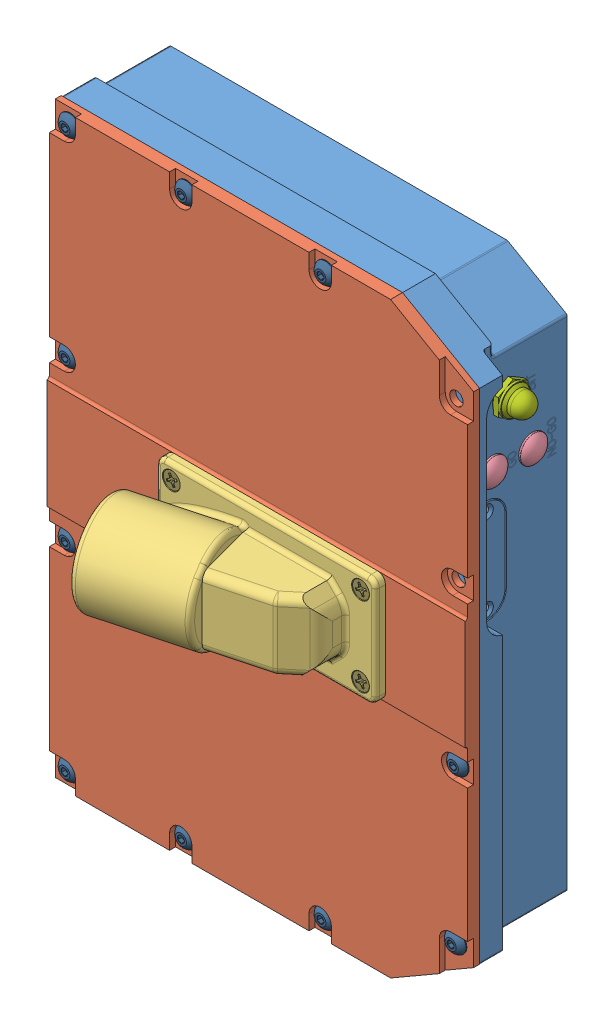
SolidWorks assembly HUD Bit Box Assembly, configuration Default. Lengths in mm.
Overall size (135.2 187.32 73.81).
243 component instances, 42 part files, 37 mates.
Components (placement in the parent):
- HUD BIT Box-1: HUD BIT Box [Default] at origin size (133.35 187.32 34.29)
- HUD BIT Box Lid-1: HUD BIT Box Lid [Default] at (0 0 34.29) size (133.35 187.32 4.6)
- HUD Camera-1: HUD Camera [Default] at (0 0 38.8937) size (72.88 34.92 34.91)
- CMC 441 XTP-1: CMC 441 XTP [CMC 441 GTP] at (130.1743 132.2705 23.8125) x (-1 0 0) z (0 0.965721 0.259583) size (10.92 8.75 8.74)
- CMC 441 XTP-2: CMC 441 XTP [CMC 441 YTP] at (130.1743 132.2705 11.1125) x (-1 0 0) z (0 0.912347 0.409418) size (10.92 8.75 8.74)
- 334-15_SLASH_X1C5-1QSA - LED, 5mm (T1.75), WHITE, 3.2V, 20mA, PTH-1: 334-15_SLASH_X1C5-1QSA - LED, 5mm (T1.75), WHITE, 3.2V, 20mA, PTH [Default] at (124.5863 132.2705 23.0425) x (0 0 1) z (0 1 0) size (5.9 33.98 5.45)
- CF18JT68R0 - RESISTOR, 68Ohms, .125W, PTH, NO LEADS-1: CF18JT68R0 - RESISTOR, 68Ohms, .125W, PTH, NO LEADS [Default] at (100.3863 132.2705 21.2645) x (-1 0 0) z (0 1 0) size (8.5 3.53 3.53)
- 334-15_SLASH_X1C5-1QSA - LED, 5mm (T1.75), WHITE, 3.2V, 20mA, PTH-2: 334-15_SLASH_X1C5-1QSA - LED, 5mm (T1.75), WHITE, 3.2V, 20mA, PTH [Default] at (124.5863 132.2705 10.3425) x (0 0 1) z (0 1 0) size (5.9 33.98 5.45)
- CF18JT68R0 - RESISTOR, 68Ohms, .125W, PTH, NO LEADS-2: CF18JT68R0 - RESISTOR, 68Ohms, .125W, PTH, NO LEADS [Default] at (100.3863 132.2705 8.5645) x (-1 0 0) z (0 1 0) size (8.5 3.53 3.53)
- N5040G 2 - DUST BOOT, GREY, .25-32, M5423-SLASH-10-01-1: N5040G 2 - DUST BOOT, GREY, .25-32, M5423-SLASH-10-01 [Default] at (133.604 150.6855 19.05) x (0 -0.866025 -0.5) z (0 -0.5 0.866025) size (9.53 8.2 11)
- 30-3UL-1: 30-3UL [Default] at (129.3812 150.6855 19.05) x (0 -1 0) z (0 0 1) size (9.53 25.53 9.53)
- 93365A130 - INSERT, 6-32, BRASS, FOR PLASTICS-1: 93365A130 - INSERT, 6-32, BRASS, FOR PLASTICS [93365A130] at (134.239 9.0805 34.29) x (0 1 0) z (1 0 0) size (5.56 4.29 5.56)
- 97763A141 - BHCS, 6-32 X .250, 18-8, BLACK-OXIDE-1: 97763A141 - BHCS, 6-32 X .250, 18-8, BLACK-OXIDE [97763A141] at (134.239 9.0805 38.0492) size (6.65 6.65 8.58)
- 93365A130 - INSERT, 6-32, BRASS, FOR PLASTICS-11: 93365A130 - INSERT, 6-32, BRASS, FOR PLASTICS [93365A130] at (111.4625 95.3643 23.8325) x (-0.984808 0.173648 0) z (0.173648 0.984808 0) size (5.56 4.29 5.56)
- 93365A120_BRASS HEAT-SET INSERT FOR PLASTICS_4-40-1: 93365A120_BRASS HEAT-SET INSERT FOR PLASTICS_4-40 [93365A120] at (109.5375 96.7105 38.8937) x (-0.98434 -0.176283 0) z (-0.176283 0.98434 0) size (4.37 3.82 4.37)
- FHS, 100 DEG, 4-40 X .375, STEEL-1: FHS, 100 DEG, 4-40 X .375, STEEL [90471A160] at (109.5375 96.7105 40.6856) x (-0.913606 -0.4066 0) z (0 0 1) size (5.38 5.38 9.77)
- 97763A141 - BHCS, 6-32 X .250, 18-8, BLACK-OXIDE-2: 97763A141 - BHCS, 6-32 X .250, 18-8, BLACK-OXIDE [97763A141] at (11.1125 109.4105 38.0492) size (6.65 6.65 8.58)
- 97763A141 - BHCS, 6-32 X .250, 18-8, BLACK-OXIDE-3: 97763A141 - BHCS, 6-32 X .250, 18-8, BLACK-OXIDE [97763A141] at (11.1125 58.6105 38.0492) size (6.65 6.65 8.58)
- 97763A141 - BHCS, 6-32 X .250, 18-8, BLACK-OXIDE-4: 97763A141 - BHCS, 6-32 X .250, 18-8, BLACK-OXIDE [97763A141] at (11.1125 -4.8895 38.0492) size (6.65 6.65 8.58)
- 97763A141 - BHCS, 6-32 X .250, 18-8, BLACK-OXIDE-5: 97763A141 - BHCS, 6-32 X .250, 18-8, BLACK-OXIDE [97763A141] at (48.26 -4.8895 38.0492) size (6.65 6.65 8.58)
- 97763A141 - BHCS, 6-32 X .250, 18-8, BLACK-OXIDE-6: 97763A141 - BHCS, 6-32 X .250, 18-8, BLACK-OXIDE [97763A141] at (92.71 -4.8895 38.0492) size (6.65 6.65 8.58)
- 97763A141 - BHCS, 6-32 X .250, 18-8, BLACK-OXIDE-7: 97763A141 - BHCS, 6-32 X .250, 18-8, BLACK-OXIDE [97763A141] at (11.1125 172.9105 38.0492) size (6.65 6.65 8.58)
- 97763A141 - BHCS, 6-32 X .250, 18-8, BLACK-OXIDE-8: 97763A141 - BHCS, 6-32 X .250, 18-8, BLACK-OXIDE [97763A141] at (134.9375 58.6105 38.0492) size (6.65 6.65 8.58)
- 97763A141 - BHCS, 6-32 X .250, 18-8, BLACK-OXIDE-9: 97763A141 - BHCS, 6-32 X .250, 18-8, BLACK-OXIDE [97763A141] at (92.71 172.9105 38.0492) size (6.65 6.65 8.58)
- 97763A141 - BHCS, 6-32 X .250, 18-8, BLACK-OXIDE-10: 97763A141 - BHCS, 6-32 X .250, 18-8, BLACK-OXIDE [97763A141] at (48.26 172.9105 38.0492) size (6.65 6.65 8.58)
- 93365A130 - INSERT, 6-32, BRASS, FOR PLASTICS-2: 93365A130 - INSERT, 6-32, BRASS, FOR PLASTICS [93365A130] at (11.1125 109.4105 34.29) x (0 1 0) z (1 0 0) size (5.56 4.29 5.56)
- 93365A130 - INSERT, 6-32, BRASS, FOR PLASTICS-3: 93365A130 - INSERT, 6-32, BRASS, FOR PLASTICS [93365A130] at (11.1125 58.6105 34.29) x (0 1 0) z (1 0 0) size (5.56 4.29 5.56)
- 93365A130 - INSERT, 6-32, BRASS, FOR PLASTICS-4: 93365A130 - INSERT, 6-32, BRASS, FOR PLASTICS [93365A130] at (11.1125 -4.8895 34.29) x (0 1 0) z (1 0 0) size (5.56 4.29 5.56)
- 93365A130 - INSERT, 6-32, BRASS, FOR PLASTICS-5: 93365A130 - INSERT, 6-32, BRASS, FOR PLASTICS [93365A130] at (48.26 -4.8895 34.29) x (0 1 0) z (1 0 0) size (5.56 4.29 5.56)
- 93365A130 - INSERT, 6-32, BRASS, FOR PLASTICS-6: 93365A130 - INSERT, 6-32, BRASS, FOR PLASTICS [93365A130] at (92.71 -4.8895 34.29) x (0 1 0) z (1 0 0) size (5.56 4.29 5.56)
- 93365A130 - INSERT, 6-32, BRASS, FOR PLASTICS-7: 93365A130 - INSERT, 6-32, BRASS, FOR PLASTICS [93365A130] at (11.1125 172.9105 34.29) x (0 1 0) z (1 0 0) size (5.56 4.29 5.56)
- 93365A130 - INSERT, 6-32, BRASS, FOR PLASTICS-8: 93365A130 - INSERT, 6-32, BRASS, FOR PLASTICS [93365A130] at (134.9375 58.6105 34.29) x (0 1 0) z (1 0 0) size (5.56 4.29 5.56)
- 93365A130 - INSERT, 6-32, BRASS, FOR PLASTICS-9: 93365A130 - INSERT, 6-32, BRASS, FOR PLASTICS [93365A130] at (92.71 172.9105 34.29) x (0 1 0) z (1 0 0) size (5.56 4.29 5.56)
- 93365A130 - INSERT, 6-32, BRASS, FOR PLASTICS-10: 93365A130 - INSERT, 6-32, BRASS, FOR PLASTICS [93365A130] at (48.26 172.9105 34.29) x (0 1 0) z (1 0 0) size (5.56 4.29 5.56)
- ufc_v4_controller-1: ufc_v4_controller [Default] at (66.9925 58.1943 23.8325) size (102.65 83.82 19.8)
- Arduino Mega 2560 R3 - DETAILED-1: Arduino Mega 2560 R3 - DETAILED [Default] at (67.0275 61.9043 11.1125) x (-1 0 0) z (0 1 0) size (109.9 15.25 53.6)
  - Arduino Mega PCB-1: Arduino Mega PCB [Default] at origin size (101.8 1.64 53.6)
  - headerFemalex18x2-1: headerFemalex18x2 [Default] at (-44.415 1.63 17.88) x (0 0 -1) z (1 0 0) size (45.72 11.5 5.08)
  - headerFemale-1: headerFemale [Default] at (-22.825 1.63 -24.23) size (2.54 11.5 2.54)
  - headerFemale-2: headerFemale [Default] at (-25.365 1.63 -24.23) size (2.54 11.5 2.54)
  - headerFemale-3: headerFemale [Default] at (2.815 1.63 24.23) size (2.54 11.5 2.54)
  - headerFemale-4: headerFemale [Default] at (-25.125 1.63 24.23) size (2.54 11.5 2.54)
  - headerFemale-5: headerFemale [Default] at (20.595 1.63 24.23) size (2.54 11.5 2.54)
  - headerFemale-6: headerFemale [Default] at (-20.285 1.63 -24.23) size (2.54 11.5 2.54)
  - headerFemale-7: headerFemale [Default] at (0.035 1.63 -24.23) size (2.54 11.5 2.54)
  - headerFemale-8: headerFemale [Default] at (5.115 1.63 -24.23) size (2.54 11.5 2.54)
  - headerFemale-9: headerFemale [Default] at (0.275 1.63 24.23) size (2.54 11.5 2.54)
  - headerFemale-10: headerFemale [Default] at (-4.805 1.63 24.23) size (2.54 11.5 2.54)
  - headerFemale-11: headerFemale [Default] at (-2.505 1.63 -24.23) size (2.54 11.5 2.54)
  - headerFemale-12: headerFemale [Default] at (-22.585 1.63 24.23) size (2.54 11.5 2.54)
  - headerFemale-13: headerFemale [Default] at (-2.265 1.63 24.23) size (2.54 11.5 2.54)
  - headerFemale-14: headerFemale [Default] at (12.735 1.63 -24.23) size (2.54 11.5 2.54)
  - headerFemale-15: headerFemale [Default] at (15.515 1.63 24.23) size (2.54 11.5 2.54)
  - headerFemale-16: headerFemale [Default] at (22.895 1.63 -24.23) size (2.54 11.5 2.54)
  - headerFemale-17: headerFemale [Default] at (10.195 1.63 -24.23) size (2.54 11.5 2.54)
  - headerFemale-18: headerFemale [Default] at (-35.525 1.63 -24.23) size (2.54 11.5 2.54)
  - headerFemale-19: headerFemale [Default] at (27.975 1.63 -24.23) size (2.54 11.5 2.54)
  - headerFemale-20: headerFemale [Default] at (30.755 1.63 24.23) size (2.54 11.5 2.54)
  - headerFemale-21: headerFemale [Default] at (-7.585 1.63 -24.23) size (2.54 11.5 2.54)
  - headerFemale-22: headerFemale [Default] at (35.835 1.63 24.23) size (2.54 11.5 2.54)
  - headerFemale-23: headerFemale [Default] at (18.055 1.63 24.23) size (2.54 11.5 2.54)
  - headerFemale-24: headerFemale [Default] at (-12.425 1.63 24.23) size (2.54 11.5 2.54)
  - headerFemale-25: headerFemale [Default] at (28.215 1.63 24.23) size (2.54 11.5 2.54)
  - headerFemale-26: headerFemale [Default] at (-7.345 1.63 24.23) size (2.54 11.5 2.54)
  - headerFemale-27: headerFemale [Default] at (17.815 1.63 -24.23) size (2.54 11.5 2.54)
  - headerFemale-28: headerFemale [Default] at (23.135 1.63 24.23) size (2.54 11.5 2.54)
  - headerFemale-29: headerFemale [Default] at (10.435 1.63 24.23) size (2.54 11.5 2.54)
  - headerFemale-30: headerFemale [Default] at (-32.985 1.63 -24.23) size (2.54 11.5 2.54)
  - headerFemale-31: headerFemale [Default] at (-10.125 1.63 -24.23) size (2.54 11.5 2.54)
  - headerFemale-32: headerFemale [Default] at (-30.445 1.63 -24.23) size (2.54 11.5 2.54)
  - headerFemale-33: headerFemale [Default] at (-17.745 1.63 -24.23) size (2.54 11.5 2.54)
  - headerFemale-34: headerFemale [Default] at (-27.665 1.63 24.23) size (2.54 11.5 2.54)
  - headerFemale-35: headerFemale [Default] at (5.355 1.63 24.23) size (2.54 11.5 2.54)
  - headerFemale-36: headerFemale [Default] at (20.355 1.63 -24.23) size (2.54 11.5 2.54)
  - headerFemale-37: headerFemale [Default] at (25.675 1.63 24.23) size (2.54 11.5 2.54)
  - headerFemale-38: headerFemale [Default] at (-17.505 1.63 24.23) size (2.54 11.5 2.54)
  - headerFemale-39: headerFemale [Default] at (-27.905 1.63 -24.23) size (2.54 11.5 2.54)
  - headerFemale-40: headerFemale [Default] at (-14.965 1.63 24.23) size (2.54 11.5 2.54)
  - headerFemale-41: headerFemale [Default] at (2.575 1.63 -24.23) size (2.54 11.5 2.54)
  - headerFemale-42: headerFemale [Default] at (33.295 1.63 24.23) size (2.54 11.5 2.54)
  - headerFemale-43: headerFemale [Default] at (25.435 1.63 -24.23) size (2.54 11.5 2.54)
  - headerFemale-44: headerFemale [Default] at (-20.045 1.63 24.23) size (2.54 11.5 2.54)
  - headerFemale-45: headerFemale [Default] at (-12.665 1.63 -24.23) size (2.54 11.5 2.54)
  - headerFemale-46: headerFemale [Default] at (15.275 1.63 -24.23) size (2.54 11.5 2.54)
  - headerFemale-47: headerFemale [Default] at (-30.205 1.63 24.23) size (2.54 11.5 2.54)
  - headerFemale-48: headerFemale [Default] at (38.375 1.63 24.23) size (2.54 11.5 2.54)
  - headerFemale-49: headerFemale [Default] at (-5.045 1.63 -24.23) size (2.54 11.5 2.54)
  - headerFemale-50: headerFemale [Default] at (7.895 1.63 24.23) size (2.54 11.5 2.54)
  - solder-1: solder [Default] at (29.4996 0 24.2186) x (-0.837169 0 -0.546944) z (-0.546944 0 0.837169) size (1.17 0.65 1.17)
  - solder-2: solder [Default] at (24.4196 0 24.2186) x (-0.837169 0 -0.546944) z (-0.546944 0 0.837169) size (1.17 0.65 1.17)
  - solder-3: solder [Default] at (-46.9277 0 -11.3414) x (-0.837169 0 -0.546944) z (-0.546944 0 0.837169) size (1.17 0.65 1.17)
  - solder-4: solder [Default] at (-46.9277 0 16.5986) x (-0.837169 0 -0.546944) z (-0.546944 0 0.837169) size (1.17 0.65 1.17)
  - solder-5: solder [Default] at (-13.6804 0 24.2186) x (-0.837169 0 -0.546944) z (-0.546944 0 0.837169) size (1.17 0.65 1.17)
  - solder-6: solder [Default] at (-44.3877 0 1.3586) x (-0.837169 0 -0.546944) z (-0.546944 0 0.837169) size (1.17 0.65 1.17)
  - solder-7: solder [Default] at (-34.2509 0 -24.251) x (-0.837169 0 -0.546944) z (-0.546944 0 0.837169) size (1.17 0.65 1.17)
  - solder-8: solder [Default] at (16.7996 0 24.2186) x (-0.837169 0 -0.546944) z (-0.546944 0 0.837169) size (1.17 0.65 1.17)
  - solder-9: solder [Default] at (-46.9277 0 -3.7214) x (-0.837169 0 -0.546944) z (-0.546944 0 0.837169) size (1.17 0.65 1.17)
  - solder-10: solder [Default] at (-31.7109 0 -24.251) x (-0.837169 0 -0.546944) z (-0.546944 0 0.837169) size (1.17 0.65 1.17)
  - solder-11: solder [Default] at (9.1796 0 24.2186) x (-0.837169 0 -0.546944) z (-0.546944 0 0.837169) size (1.17 0.65 1.17)
  - solder-12: solder [Default] at (-39.3309 0 -24.251) x (-0.837169 0 -0.546944) z (-0.546944 0 0.837169) size (1.17 0.65 1.17)
  - solder-13: solder [Default] at (-44.3877 0 -16.4214) x (-0.837169 0 -0.546944) z (-0.546944 0 0.837169) size (1.17 0.65 1.17)
  - solder-14: solder [Default] at (14.0091 0 -24.251) x (-0.837169 0 -0.546944) z (-0.546944 0 0.837169) size (1.17 0.65 1.17)
  - solder-15: solder [Default] at (11.4691 0 -24.251) x (-0.837169 0 -0.546944) z (-0.546944 0 0.837169) size (1.17 0.65 1.17)
  - solder-16: solder [Default] at (-46.9277 0 -13.8814) x (-0.837169 0 -0.546944) z (-0.546944 0 0.837169) size (1.17 0.65 1.17)
  - solder-17: solder [Default] at (3.8491 0 -24.251) x (-0.837169 0 -0.546944) z (-0.546944 0 0.837169) size (1.17 0.65 1.17)
  - solder-18: solder [Default] at (8.9291 0 -24.251) x (-0.837169 0 -0.546944) z (-0.546944 0 0.837169) size (1.17 0.65 1.17)
  - solder-19: solder [Default] at (-46.9277 0 6.4386) x (-0.837169 0 -0.546944) z (-0.546944 0 0.837169) size (1.17 0.65 1.17)
  - solder-20: solder [Default] at (-3.7709 0 -24.251) x (-0.837169 0 -0.546944) z (-0.546944 0 0.837169) size (1.17 0.65 1.17)
  - solder-21: solder [Default] at (-46.9277 0 -18.9614) x (-0.837169 0 -0.546944) z (-0.546944 0 0.837169) size (1.17 0.65 1.17)
  - solder-22: solder [Default] at (-13.9309 0 -24.251) x (-0.837169 0 -0.546944) z (-0.546944 0 0.837169) size (1.17 0.65 1.17)
  - solder-23: solder [Default] at (-11.3909 0 -24.251) x (-0.837169 0 -0.546944) z (-0.546944 0 0.837169) size (1.17 0.65 1.17)
  - solder-24: solder [Default] at (-44.3877 0 24.2186) x (-0.837169 0 -0.546944) z (-0.546944 0 0.837169) size (1.17 0.65 1.17)
  - solder-25: solder [Default] at (-44.3877 0 -18.9614) x (-0.837169 0 -0.546944) z (-0.546944 0 0.837169) size (1.17 0.65 1.17)
  - solder-26: solder [Default] at (-8.8509 0 -24.251) x (-0.837169 0 -0.546944) z (-0.546944 0 0.837169) size (1.17 0.65 1.17)
  - solder-27: solder [Default] at (45.1853 0 12.6794) x (-0.837169 0 -0.546944) z (-0.546944 0 0.837169) size (1.17 0.65 1.17)
  - solder-28: solder [Default] at (-23.8404 0 24.2186) x (-0.837169 0 -0.546944) z (-0.546944 0 0.837169) size (1.17 0.65 1.17)
  - solder-29: solder [Default] at (-44.3877 0 16.5986) x (-0.837169 0 -0.546944) z (-0.546944 0 0.837169) size (1.17 0.65 1.17)
  - solder-30: solder [Default] at (19.0891 0 -24.251) x (-0.837169 0 -0.546944) z (-0.546944 0 0.837169) size (1.17 0.65 1.17)
  - solder-31: solder [Default] at (-34.0004 0 24.2186) x (-0.837169 0 -0.546944) z (-0.546944 0 0.837169) size (1.17 0.65 1.17)
  - solder-32: solder [Default] at (-3.5204 0 24.2186) x (-0.837169 0 -0.546944) z (-0.546944 0 0.837169) size (1.17 0.65 1.17)
  - solder-33: solder [Default] at (-46.9277 0 3.8986) x (-0.837169 0 -0.546944) z (-0.546944 0 0.837169) size (1.17 0.65 1.17)
  - solder-34: solder [Default] at (1.5596 0 24.2186) x (-0.837169 0 -0.546944) z (-0.546944 0 0.837169) size (1.17 0.65 1.17)
  - solder-35: solder [Default] at (19.3396 0 24.2186) x (-0.837169 0 -0.546944) z (-0.546944 0 0.837169) size (1.17 0.65 1.17)
  - solder-36: solder [Default] at (-18.7604 0 24.2186) x (-0.837169 0 -0.546944) z (-0.546944 0 0.837169) size (1.17 0.65 1.17)
  - solder-37: solder [Default] at (-44.3877 0 -8.8014) x (-0.837169 0 -0.546944) z (-0.546944 0 0.837169) size (1.17 0.65 1.17)
  - solder-38: solder [Default] at (16.5491 0 -24.251) x (-0.837169 0 -0.546944) z (-0.546944 0 0.837169) size (1.17 0.65 1.17)
  - solder-39: solder [Default] at (45.1853 0 15.1294) x (-0.837169 0 -0.546944) z (-0.546944 0 0.837169) size (1.17 0.65 1.17)
  - solder-40: solder [Default] at (-46.9277 0 19.1386) x (-0.837169 0 -0.546944) z (-0.546944 0 0.837169) size (1.17 0.65 1.17)
  - solder-41: solder [Default] at (-31.4604 0 24.2186) x (-0.837169 0 -0.546944) z (-0.546944 0 0.837169) size (1.17 0.65 1.17)
  - solder-42: solder [Default] at (21.8796 0 24.2186) x (-0.837169 0 -0.546944) z (-0.546944 0 0.837169) size (1.17 0.65 1.17)
  - solder-43: solder [Default] at (-46.9277 0 -1.1814) x (-0.837169 0 -0.546944) z (-0.546944 0 0.837169) size (1.17 0.65 1.17)
  - solder-44: solder [Default] at (-11.1404 0 24.2186) x (-0.837169 0 -0.546944) z (-0.546944 0 0.837169) size (1.17 0.65 1.17)
  - solder-45: solder [Default] at (-21.3004 0 24.2186) x (-0.837169 0 -0.546944) z (-0.546944 0 0.837169) size (1.17 0.65 1.17)
  - solder-46: solder [Default] at (-36.5404 0 24.2186) x (-0.837169 0 -0.546944) z (-0.546944 0 0.837169) size (1.17 0.65 1.17)
  - solder-47: solder [Default] at (-24.0909 0 -24.251) x (-0.837169 0 -0.546944) z (-0.546944 0 0.837169) size (1.17 0.65 1.17)
  - solder-48: solder [Default] at (-36.7909 0 -24.251) x (-0.837169 0 -0.546944) z (-0.546944 0 0.837169) size (1.17 0.65 1.17)
  - solder-49: solder [Default] at (-44.3877 0 19.1386) x (-0.837169 0 -0.546944) z (-0.546944 0 0.837169) size (1.17 0.65 1.17)
  - solder-50: solder [Default] at (-46.9277 0 14.0586) x (-0.837169 0 -0.546944) z (-0.546944 0 0.837169) size (1.17 0.65 1.17)
  - solder-51: solder [Default] at (32.0396 0 24.2186) x (-0.837169 0 -0.546944) z (-0.546944 0 0.837169) size (1.17 0.65 1.17)
  - solder-52: solder [Default] at (-44.3877 0 -11.3414) x (-0.837169 0 -0.546944) z (-0.546944 0 0.837169) size (1.17 0.65 1.17)
  - solder-53: solder [Default] at (-0.9804 0 24.2186) x (-0.837169 0 -0.546944) z (-0.546944 0 0.837169) size (1.17 0.65 1.17)
  - solder-54: solder [Default] at (-44.3877 0 11.5186) x (-0.837169 0 -0.546944) z (-0.546944 0 0.837169) size (1.17 0.65 1.17)
  - solder-55: solder [Default] at (-44.3877 0 8.9786) x (-0.837169 0 -0.546944) z (-0.546944 0 0.837169) size (1.17 0.65 1.17)
  - solder-56: solder [Default] at (-28.9204 0 24.2186) x (-0.837169 0 -0.546944) z (-0.546944 0 0.837169) size (1.17 0.65 1.17)
  - solder-57: solder [Default] at (-41.8709 0 -24.251) x (-0.837169 0 -0.546944) z (-0.546944 0 0.837169) size (1.17 0.65 1.17)
  - solder-58: solder [Default] at (-46.9277 0 -16.4214) x (-0.837169 0 -0.546944) z (-0.546944 0 0.837169) size (1.17 0.65 1.17)
  - solder-59: solder [Default] at (21.6291 0 -24.251) x (-0.837169 0 -0.546944) z (-0.546944 0 0.837169) size (1.17 0.65 1.17)
  - solder-60: solder [Default] at (-26.6309 0 -24.251) x (-0.837169 0 -0.546944) z (-0.546944 0 0.837169) size (1.17 0.65 1.17)
  - solder-61: solder [Default] at (-46.9277 0 8.9786) x (-0.837169 0 -0.546944) z (-0.546944 0 0.837169) size (1.17 0.65 1.17)
  - solder-62: solder [Default] at (-8.6004 0 24.2186) x (-0.837169 0 -0.546944) z (-0.546944 0 0.837169) size (1.17 0.65 1.17)
  - solder-63: solder [Default] at (-44.3877 0 6.4386) x (-0.837169 0 -0.546944) z (-0.546944 0 0.837169) size (1.17 0.65 1.17)
  - solder-64: solder [Default] at (-46.9277 0 -8.8014) x (-0.837169 0 -0.546944) z (-0.546944 0 0.837169) size (1.17 0.65 1.17)
  - solder-65: solder [Default] at (6.3891 0 -24.251) x (-0.837169 0 -0.546944) z (-0.546944 0 0.837169) size (1.17 0.65 1.17)
  - solder-66: solder [Default] at (-6.3109 0 -24.251) x (-0.837169 0 -0.546944) z (-0.546944 0 0.837169) size (1.17 0.65 1.17)
  - solder-67: solder [Default] at (-44.3877 0 -13.8814) x (-0.837169 0 -0.546944) z (-0.546944 0 0.837169) size (1.17 0.65 1.17)
  - solder-68: solder [Default] at (-6.0604 0 24.2186) x (-0.837169 0 -0.546944) z (-0.546944 0 0.837169) size (1.17 0.65 1.17)
  - solder-69: solder [Default] at (-44.3877 0 -1.1814) x (-0.837169 0 -0.546944) z (-0.546944 0 0.837169) size (1.17 0.65 1.17)
  - solder-70: solder [Default] at (-26.3804 0 24.2186) x (-0.837169 0 -0.546944) z (-0.546944 0 0.837169) size (1.17 0.65 1.17)
  - solder-71: solder [Default] at (43.2353 0 15.1294) x (-0.837169 0 -0.546944) z (-0.546944 0 0.837169) size (1.17 0.65 1.17)
  - solder-72: solder [Default] at (-44.3877 0 14.0586) x (-0.837169 0 -0.546944) z (-0.546944 0 0.837169) size (1.17 0.65 1.17)
  - solder-73: solder [Default] at (43.2353 0 12.6794) x (-0.837169 0 -0.546944) z (-0.546944 0 0.837169) size (1.17 0.65 1.17)
  - solder-74: solder [Default] at (-46.9277 0 24.2186) x (-0.837169 0 -0.546944) z (-0.546944 0 0.837169) size (1.17 0.65 1.17)
  - solder-75: solder [Default] at (-29.1709 0 -24.251) x (-0.837169 0 -0.546944) z (-0.546944 0 0.837169) size (1.17 0.65 1.17)
  - solder-76: solder [Default] at (-44.3877 0 -3.7214) x (-0.837169 0 -0.546944) z (-0.546944 0 0.837169) size (1.17 0.65 1.17)
  - solder-77: solder [Default] at (-46.9277 0 21.6786) x (-0.837169 0 -0.546944) z (-0.546944 0 0.837169) size (1.17 0.65 1.17)
  - solder-78: solder [Default] at (-46.9277 0 1.3586) x (-0.837169 0 -0.546944) z (-0.546944 0 0.837169) size (1.17 0.65 1.17)
  - solder-79: solder [Default] at (26.9596 0 24.2186) x (-0.837169 0 -0.546944) z (-0.546944 0 0.837169) size (1.17 0.65 1.17)
  - solder-80: solder [Default] at (-44.3877 0 21.6786) x (-0.837169 0 -0.546944) z (-0.546944 0 0.837169) size (1.17 0.65 1.17)
  - solder-81: solder [Default] at (4.0996 0 24.2186) x (-0.837169 0 -0.546944) z (-0.546944 0 0.837169) size (1.17 0.65 1.17)
  - solder-82: solder [Default] at (-46.9277 0 -6.2614) x (-0.837169 0 -0.546944) z (-0.546944 0 0.837169) size (1.17 0.65 1.17)
  - solder-83: solder [Default] at (-44.3877 0 3.8986) x (-0.837169 0 -0.546944) z (-0.546944 0 0.837169) size (1.17 0.65 1.17)
  - solder-84: solder [Default] at (-16.4709 0 -24.251) x (-0.837169 0 -0.546944) z (-0.546944 0 0.837169) size (1.17 0.65 1.17)
  - solder-85: solder [Default] at (14.2596 0 24.2186) x (-0.837169 0 -0.546944) z (-0.546944 0 0.837169) size (1.17 0.65 1.17)
  - solder-86: solder [Default] at (11.7196 0 24.2186) x (-0.837169 0 -0.546944) z (-0.546944 0 0.837169) size (1.17 0.65 1.17)
  - solder-87: solder [Default] at (-46.9277 0 11.5186) x (-0.837169 0 -0.546944) z (-0.546944 0 0.837169) size (1.17 0.65 1.17)
  - solder-88: solder [Default] at (-44.3877 0 -6.2614) x (-0.837169 0 -0.546944) z (-0.546944 0 0.837169) size (1.17 0.65 1.17)
  - solder-89: solder [Default] at (-1.2309 0 -24.251) x (-0.837169 0 -0.546944) z (-0.546944 0 0.837169) size (1.17 0.65 1.17)
  - solder-90: solder [Default] at (-19.0109 0 -24.251) x (-0.837169 0 -0.546944) z (-0.546944 0 0.837169) size (1.17 0.65 1.17)
  - USBInput-1: USBInput [Default] at (51.825 1.63 -24.14) x (0 0 1) z (-1 0 0) size (13.72 15.2 16.5)
  - solder1.8-1: solder1.8 [Default] at (47.8972 0 19.9763) x (-0.837169 0 -0.546944) z (-0.546944 0 0.837169) size (1.8 0.65 1.8)
  - solder1.8-2: solder1.8 [Default] at (47.8972 0 7.7416) x (-0.837169 0 -0.546944) z (-0.546944 0 0.837169) size (1.8 0.65 1.8)
  - PowerPlug-1: PowerPlug [Default] at (53.07 1.63 -23.075) x (0 0 1) z (-1 0 0) size (11.2 15.2 15.9)
  - smdPushButton-1: smdPushButton [Default] at (-25.845 1.63 0) x (0 0 -1) z (1 0 0) size (9.1 2.85 5.6)
  - headerMale-1: headerMale [Default] at (-17.525 1.63 2.54) size (2.54 11.1 2.54)
  - headerMale-2: headerMale [Default] at (-14.985 1.63 -2.36) size (2.54 11.1 2.54)
  - headerMale-3: headerMale [Default] at (-17.525 1.63 -2.36) size (2.54 11.1 2.54)
  - headerMale-4: headerMale [Default] at (-14.985 1.63 0.09) size (2.54 11.1 2.54)
  - headerMale-5: headerMale [Default] at (-17.525 1.63 0.09) size (2.54 11.1 2.54)
  - headerMale-6: headerMale [Default] at (-14.985 1.63 2.54) size (2.54 11.1 2.54)
  - smd47-1: smd47 [Default] at (33.2359 2.48 -17.65) x (0 0 1) z (-1 0 0) size (9.5 5.61 6.5)
  - smd47-2: smd47 [Default] at (26.7359 2.48 -17.65) x (0 0 1) z (-1 0 0) size (9.5 5.61 6.5)
  - smdM7diode-1: smdM7diode [Default] at (28.3956 1.68 -24.2569) size (6.5 2.13 2.5)
  - smdCrystalOscillator-1: smdCrystalOscillator [Default] at (29.1027 1.83 15.1887) size (11.93 3.7 4.5)
  - VoltageRegulatorAMS1112-1: VoltageRegulatorAMS1112 [Default] at (46.1008 1.63 -6.698) x (-0.008727 0 0.999962) z (-0.999962 0 -0.008727) size (5.5 1.65 6.7)
  - smdChip16pin-1: smdChip16pin [Default] at (36.9716 2.355 6.6448) x (0 0 1) z (-1 0 0) size (7.3 1.22 10)
  - tinyVoltageRegulator-1: tinyVoltageRegulator [Default] at (44.8587 1.63 1.7682) x (-0.008727 0 0.999962) z (-0.999962 0 -0.008727) size (2.75 0.7 2.1)
  - smdResistor102-1: smdResistor102 [Default] at (18.9101 1.63 -5.1619) size (2.54 0.62 1.34)
  - smdResistor102-2: smdResistor102 [Default] at (22.6192 1.63 5.022) size (2.54 0.62 1.34)
  - smdResistor102-3: smdResistor102 [Default] at (22.6192 1.63 6.9092) size (2.54 0.62 1.34)
  - smdResistor102-4: smdResistor102 [Default] at (15.0665 1.63 -5.1619) size (2.54 0.62 1.34)
  - smdLED-1: smdLED [Default] at (18.6733 1.68 4.9107) size (3.2 0.84 1.28)
  - smdLED-2: smdLED [Default] at (18.924 1.68 -8.0155) size (3.2 0.84 1.28)
  - smdLED-3: smdLED [Default] at (18.6733 1.68 6.7615) size (3.2 0.84 1.28)
  - smdLED-4: smdLED [Default] at (15.1024 1.68 -8.0155) size (3.2 0.84 1.28)
  - tinyCrystal-1: tinyCrystal [Default] at (17.0851 1.63 -14.2329) x (-0.008727 0 0.999962) z (-0.999962 0 -0.008727) size (3.1 0.8 1.45)
  - smdceramiccapacitorwhite-1: smdceramiccapacitorwhite [Default] at (22.5361 1.63 10.8878) size (2.55 0.62 1.3)
  - smdceramiccapacitorwhite-2: smdceramiccapacitorwhite [Default] at (25.6965 1.63 18.6432) size (2.55 0.62 1.3)
  - smdceramiccapacitorwhite-3: smdceramiccapacitorwhite [Default] at (33.3846 1.63 18.6432) size (2.55 0.62 1.3)
  - smdceramiccapacitorwhite-4: smdceramiccapacitorwhite [Default] at (15.9897 1.63 -17.0687) size (2.55 0.62 1.3)
  - smdceramiccapacitorwhite-5: smdceramiccapacitorwhite [Default] at (15.9897 1.63 -11.5964) size (2.55 0.62 1.3)
  - smdResistor105-1: smdResistor105 [Default] at (14.9012 1.63 -14.3439) x (0.008727 0 -0.999962) z (0.999962 0 0.008727) size (2.54 0.62 1.34)
  - smdResistor105-2: smdResistor105 [Default] at (29.3693 1.63 18.6473) size (2.54 0.62 1.34)
  - tinyDiode-1: tinyDiode [Default] at (19.1387 1.64 -14.1257) x (0.008727 0 -0.999962) z (0.999962 0 0.008727) size (2.77 0.81 1)
  - smdResistor103-1: smdResistor103 [Default] at (34.5333 1.63 -4.0924) size (2.54 0.62 1.34)
  - smdResistor103-2: smdResistor103 [Default] at (18.6293 1.63 8.8506) size (2.54 0.62 1.34)
  - smdResistor103-3: smdResistor103 [Default] at (30.4879 1.63 -4.0203) size (2.54 0.62 1.34)
  - smdceramiccapacitor-1: smdceramiccapacitor [Default] at (22.5508 1.63 -0.8918) size (2.55 0.62 1.3)
  - smdceramiccapacitor-2: smdceramiccapacitor [Default] at (22.5508 1.63 8.9496) size (2.55 0.62 1.3)
  - smdceramiccapacitor-3: smdceramiccapacitor [Default] at (39.1596 1.63 7.9308) size (2.55 0.62 1.3)
  - smdceramiccapacitor-4: smdceramiccapacitor [Default] at (39.1596 1.63 17.5628) size (2.55 0.62 1.3)
  - smdceramiccapacitor-5: smdceramiccapacitor [Default] at (39.1596 1.63 19.5386) size (2.55 0.62 1.3)
  - smdceramiccapacitor-6: smdceramiccapacitor [Default] at (18.6684 1.63 10.7899) size (2.55 0.62 1.3)
  - smdceramiccapacitor-7: smdceramiccapacitor [Default] at (34.4647 1.63 -7.4993) x (0.008727 0 -0.999962) z (0.999962 0 0.008727) size (2.55 0.62 1.3)
  - smdceramiccapacitor-8: smdceramiccapacitor [Default] at (38.0044 1.63 -4.0975) size (2.55 0.62 1.3)
  - smdceramiccapacitor-9: smdceramiccapacitor [Default] at (26.4038 1.7166 -4.0641) size (2.55 0.62 1.3)
  - tinyVoltageRegulator5pins-1: tinyVoltageRegulator5pins [Default] at (36.9485 1.63 -7.6363) x (-0.008727 0 0.999962) z (-0.999962 0 -0.008727) size (2.75 0.7 2.1)
  - smdResistorNoNumber-1: smdResistorNoNumber [Default] at (22.6869 1.63 3.0647) size (2.54 0.61 1.34)
  - smdResistorNoNumber-2: smdResistorNoNumber [Default] at (39.1794 1.63 11.6814) size (2.54 0.61 1.34)
  - smdResistorNoNumber-3: smdResistorNoNumber [Default] at (39.1794 1.63 13.8493) size (2.54 0.61 1.34)
  - smdResistorNoNumber-4: smdResistorNoNumber [Default] at (22.6869 1.63 1.2353) size (2.54 0.61 1.34)
  - 1.7mmSmdCeramicCapacitorgray-1: 1.7mmSmdCeramicCapacitorgray [Default] at (39.277 1.5726 9.803) size (2.04 0.5 1.04)
  - 1.7mmSmdCeramicCapacitorgray-2: 1.7mmSmdCeramicCapacitorgray [Default] at (39.277 1.5726 15.6439) size (2.04 0.5 1.04)
  - CrystalNo5-1: CrystalNo5 [Default] at (48.5405 1.68 1.8508) x (0.008727 0 -0.999962) z (0.999962 0 0.008727) size (2.54 0.66 1.44)
  - smdChip8pin-1: smdChip8pin [Default] at (28.6276 2.355 -10.7802) size (7.3 1.22 4.5)
  - ATmega 2560-1: ATmega 2560 [Default] at (0.3651 1.63 0.2251) size (16.31 1.01 16.31)
- 93365A130 - INSERT, 6-32, BRASS, FOR PLASTICS-14: 93365A130 - INSERT, 6-32, BRASS, FOR PLASTICS [93365A130] at (111.4625 21.2843 23.8325) x (-0.984808 0.173648 0) z (0.173648 0.984808 0) size (5.56 4.29 5.56)
- 93365A130 - INSERT, 6-32, BRASS, FOR PLASTICS-15: 93365A130 - INSERT, 6-32, BRASS, FOR PLASTICS [93365A130] at (22.4625 95.3643 23.8325) x (-0.984808 0.173648 0) z (0.173648 0.984808 0) size (5.56 4.29 5.56)
- 93365A120_BRASS HEAT-SET INSERT FOR PLASTICS_4-40-2: 93365A120_BRASS HEAT-SET INSERT FOR PLASTICS_4-40 [93365A120] at (49.2125 96.7105 38.8937) x (-0.98434 -0.176283 0) z (-0.176283 0.98434 0) size (4.37 3.82 4.37)
- 93365A120_BRASS HEAT-SET INSERT FOR PLASTICS_4-40-3: 93365A120_BRASS HEAT-SET INSERT FOR PLASTICS_4-40 [93365A120] at (109.5375 71.3105 38.8937) x (-0.98434 -0.176283 0) z (-0.176283 0.98434 0) size (4.37 3.82 4.37)
- 93365A120_BRASS HEAT-SET INSERT FOR PLASTICS_4-40-4: 93365A120_BRASS HEAT-SET INSERT FOR PLASTICS_4-40 [93365A120] at (49.2125 71.3105 38.8937) x (-0.98434 -0.176283 0) z (-0.176283 0.98434 0) size (4.37 3.82 4.37)
- FHS, 100 DEG, 4-40 X .375, STEEL-2: FHS, 100 DEG, 4-40 X .375, STEEL [90471A160] at (49.2125 96.7105 40.6856) x (-0.913606 -0.4066 0) z (0 0 1) size (5.38 5.38 9.77)
- FHS, 100 DEG, 4-40 X .375, STEEL-3: FHS, 100 DEG, 4-40 X .375, STEEL [90471A160] at (109.5375 71.3105 40.6856) x (-0.913606 -0.4066 0) z (0 0 1) size (5.38 5.38 9.77)
- FHS, 100 DEG, 4-40 X .375, STEEL-4: FHS, 100 DEG, 4-40 X .375, STEEL [90471A160] at (49.2125 71.3105 40.6856) x (-0.913606 -0.4066 0) z (0 0 1) size (5.38 5.38 9.77)
Mates (geometry in assembly coordinates):
- Coincident34: coincident anti-aligned: plane of HUD BIT Box-1 through (133.35 4.5215 23.8125) normal (1 0 0); circle of CMC 441 XTP-1
- Concentric20: concentric: cylinder of CMC 441 XTP-1 through (130.1743 132.2705 23.8125) axis (-1 0 0) radius 3.0472; cylinder of 334-15_SLASH_X1C5-1QSA - LED, 5mm (T1.75), WHITE, 3.2V, 20mA, PTH-1 through (133.5673 132.2705 23.8125) axis (-1 0 0) radius 2.5
- Coincident43: coincident: plane of CMC 441 XTP-1 through (124.9673 131.3474 27.2467) normal (-1 0 0); plane of 334-15_SLASH_X1C5-1QSA - LED, 5mm (T1.75), WHITE, 3.2V, 20mA, PTH-1 through (124.9673 132.2705 23.8125) normal (-1 0 0)
- Coincident35: coincident anti-aligned: plane of HUD BIT Box-1 through (133.35 4.5215 23.8125) normal (1 0 0); circle of CMC 441 XTP-2
- Concentric21: concentric: cylinder of CMC 441 XTP-2 through (130.1743 132.2705 11.1125) axis (-1 0 0) radius 3.0472; cylinder of 334-15_SLASH_X1C5-1QSA - LED, 5mm (T1.75), WHITE, 3.2V, 20mA, PTH-2 through (133.5673 132.2705 11.1125) axis (-1 0 0) radius 2.5
- Coincident41: coincident anti-aligned: plane of HUD BIT Box-1 through (133.35 4.5215 23.8125) normal (1 0 0); plane of N5040G 2 - DUST BOOT, GREY, .25-32, M5423-SLASH-10-01-1 through (133.35 153.0668 14.9256) normal (-1 0 0)
- Parallel4: parallel aligned: plane of HUD BIT Box-1 through (0 0 34.29) normal (0 0 1); plane of N5040G 2 - DUST BOOT, GREY, .25-32, M5423-SLASH-10-01-1 through (135.1915 153.4351 23.8125) normal (0 0 1)
- Concentric18: concentric anti-aligned: cylinder of HUD BIT Box-1 through (133.35 150.6855 19.05) axis (1 0 0) radius 3.5712; cylinder of 30-3UL-1 through (135.7312 150.6855 19.05) axis (-1 0 0) radius 3.175
- Coincident39: coincident: plane of HUD BIT Box-1 through (129.3812 150.6855 19.05) normal (-1 0 0); plane of ? through (66.675 163.83 279.4) normal (0 0 1)
- Coincident40: coincident anti-aligned: plane of HUD BIT Box-1 through (129.3812 150.6855 19.05) normal (-1 0 0); plane of 30-3UL-1 through (129.3812 150.6855 19.05) normal (1 0 0)
- Parallel2: parallel anti-aligned: plane of HUD BIT Box-1 through (113.8746 172.9105 -189.6815) normal (0 -1 0); plane of 30-3UL-1 through (114.0143 148.1614 17.4625) normal (0 1 0)
- Coincident42: coincident: plane of HUD BIT Box-1 through (128.5875 164.416 -213.1038) normal (-1 0 0); plane of 30-3UL-1 through (129.3812 150.6855 19.05) normal (1 0 0)
- ProfileCenter1: profile center anti-aligned: plane of CF18JT68R0 - RESISTOR, 68Ohms, .125W, PTH, NO LEADS-1 through (99.5863 132.2705 21.2645) normal (1 0 0); plane of 334-15_SLASH_X1C5-1QSA - LED, 5mm (T1.75), WHITE, 3.2V, 20mA, PTH-1 through (99.5863 132.2705 23.0425) normal (-1 0 0)
- Coincident46: coincident aligned: plane of 334-15_SLASH_X1C5-1QSA - LED, 5mm (T1.75), WHITE, 3.2V, 20mA, PTH-1 through (124.9673 132.2705 23.8125) normal (-1 0 0); plane of 334-15_SLASH_X1C5-1QSA - LED, 5mm (T1.75), WHITE, 3.2V, 20mA, PTH-2 through (124.9673 132.2705 11.1125) normal (-1 0 0)
- Coincident47: coincident aligned: plane of 334-15_SLASH_X1C5-1QSA - LED, 5mm (T1.75), WHITE, 3.2V, 20mA, PTH-1 through (124.9673 131.7705 22.5425) normal (0 -1 0); plane of 334-15_SLASH_X1C5-1QSA - LED, 5mm (T1.75), WHITE, 3.2V, 20mA, PTH-2 through (124.9673 131.7705 9.8425) normal (0 -1 0)
- ProfileCenter2: profile center anti-aligned: plane of CF18JT68R0 - RESISTOR, 68Ohms, .125W, PTH, NO LEADS-2 through (99.5863 132.2705 8.5645) normal (1 0 0); plane of 334-15_SLASH_X1C5-1QSA - LED, 5mm (T1.75), WHITE, 3.2V, 20mA, PTH-2 through (99.5863 132.2705 10.3425) normal (-1 0 0)
- Concentric22: concentric aligned: cylinder of HUD BIT Box-1 through (134.239 9.0805 34.29) axis (0 0 1) radius 2.5273; cylinder of 93365A130 - INSERT, 6-32, BRASS, FOR PLASTICS-1 through (134.239 9.0805 34.29) axis (0 0 1) radius 2.5273
- Coincident48: coincident aligned: plane of HUD BIT Box-1 through (0 0 34.29) normal (0 0 1); plane of 93365A130 - INSERT, 6-32, BRASS, FOR PLASTICS-1 through (134.239 9.0805 34.29) normal (0 0 1)
- Concentric23: concentric aligned: cylinder of HUD BIT Box-1 through (134.239 9.0805 34.29) axis (0 0 1) radius 2.5273; cylinder of 97763A141 - BHCS, 6-32 X .250, 18-8, BLACK-OXIDE-1 through (134.239 9.0805 38.0492) axis (0 0 1) radius 3.3274
- Coincident49: coincident anti-aligned: plane of HUD BIT Box Lid-1 through (136.3916 9.0805 36.195) normal (0 0 1); plane of 97763A141 - BHCS, 6-32 X .250, 18-8, BLACK-OXIDE-1 through (134.239 5.7531 36.195) normal (0 0 -1)
- InPlace1: in place: plane of HUD BIT Box Lid-1 through (0 0 38.8937) normal (0 0 1); plane of HUD Camera-1 through (0 0 38.8937) normal (0 0 1); moOrthogonalPlaneRef_w of HUD BIT Box Lid-1 through (0 0 38.8937) normal (0 0 1); plane of HUD Camera-1 through (0 0 38.8937) normal (0 1 0); plane of HUD BIT Box Lid-1 through (0 0 38.8937) normal (0 0 1); plane of HUD Camera-1 through (0 0 38.8937) normal (1 0 0); plane of HUD BIT Box Lid-1 through (0 0 38.8937) normal (0 0 1); unknown of HUD Camera-1
- Coincident50: coincident aligned: plane of HUD BIT Box Lid-1; plane of HUD Camera-1
- Coincident51: coincident aligned: moOrthogonalPlaneRef_w of HUD BIT Box Lid-1 through (0 0 38.8937) normal (0 1 0); plane of HUD Camera-1 through (0 0 38.8937) normal (0 1 0)
- Coincident52: coincident anti-aligned: moOrthogonalPlaneRef_w of HUD BIT Box Lid-1 through (0 0 38.8937) normal (-1 0 0); plane of HUD Camera-1 through (0 0 38.8937) normal (1 0 0)
- Concentric24: concentric anti-aligned: cylinder of HUD BIT Box Lid-1 through (109.5375 96.7105 38.8937) axis (0 0 1) radius 1.7272; circle of 91841A005 - NUT, 4-40, 18-8-1
- Coincident53: coincident anti-aligned: plane of HUD BIT Box Lid-1 through (0 0 34.29) normal (0 0 -1); plane of 91841A005 - NUT, 4-40, 18-8-1 through (107.3609 93.7604 34.29) normal (0 0 1)
- Width1: width aligned: plane of Arduino Mega 2560 R3 - DETAILED-1/headerFemalex18x2-1 through (115.2525 44.4743 12.7425) normal (1 0 0); plane of ufc_v4_controller-1 through (110.1725 44.4743 21.2425) normal (-1 0 0); plane of Arduino Mega 2560 R3 - DETAILED-1/headerFemalex18x2-1 through (115.2525 43.9703 23.7825) normal (1 0 0); plane of ufc_v4_controller-1 through (110.1725 41.9383 23.7825) normal (-1 0 0)
- Width2: width anti-aligned: plane of ufc_v4_controller-1 through (114.9985 41.6843 23.7825) normal (0 -1 0); plane of Arduino Mega 2560 R3 - DETAILED-1/headerFemalex18x2-1 through (110.4265 87.4043 23.7825) normal (0 1 0); plane of ufc_v4_controller-1 through (112.7125 87.4043 9.7425) normal (0 1 0); plane of Arduino Mega 2560 R3 - DETAILED-1/headerFemalex18x2-1 through (115.2525 41.6843 9.7425) normal (0 -1 0)
- Coincident61: coincident anti-aligned: plane of ufc_v4_controller-1 through (112.7125 64.5443 21.2425) normal (0 0 -1); plane of Arduino Mega 2560 R3 - DETAILED-1/headerFemalex18x2-1 through (112.7125 44.4743 21.2425) normal (0 0 1)
- Distance1: distance = 6.35 mm anti-aligned: plane of Arduino Mega 2560 R3 - DETAILED-1/Arduino Mega PCB-1 through (67.0275 61.9043 11.1125) normal (0 0 -1); plane of HUD BIT Box-1 through (0 0 4.7625) normal (0 0 1)
- Coincident62: coincident: line of HUD BIT Box-1 through (11.1125 51.0043 7.9375) axis (0 0 1); plane of Arduino Mega 2560 R3 - DETAILED-1/PowerPlug-1 through (15.5525 51.0043 23.2425) normal (0 1 0)
- Distance2: distance = 6.35 mm anti-aligned: plane of ufc_v4_controller-1 through (17.4625 16.2843 23.8325) normal (-1 0 0); plane of HUD BIT Box-1 through (11.1125 53.5432 -189.6815) normal (1 0 0)
- Concentric32: concentric anti-aligned: cone of HUD BIT Box-1 through (111.4625 95.3643 23.8325) axis (0 0 -1); cylinder of 93365A130 - INSERT, 6-32, BRASS, FOR PLASTICS-11 through (111.4625 95.3643 23.8325) axis (0 0 1) radius 2.5273
- Coincident64: coincident aligned: plane of HUD BIT Box-1 through (66.9925 58.1943 23.8325) normal (0 0 1); plane of 93365A130 - INSERT, 6-32, BRASS, FOR PLASTICS-11 through (111.4625 95.3643 23.8325) normal (0 0 1)
- Concentric33: concentric anti-aligned: cone of HUD BIT Box Lid-1 through (109.5375 96.7105 38.8937) axis (0 0 -1); cylinder of 93365A120_BRASS HEAT-SET INSERT FOR PLASTICS_4-40-1 through (109.5375 96.7105 38.8937) axis (0 0 1) radius 1.9431
- Coincident65: coincident aligned: plane of HUD BIT Box Lid-1 through (0 0 38.8937) normal (0 0 1); plane of 93365A120_BRASS HEAT-SET INSERT FOR PLASTICS_4-40-1 through (109.5375 96.7105 38.8937) normal (0 0 1)
- Coincident66: coincident aligned: cone of HUD Camera-1 through (109.5375 96.7105 42.0688) axis (0 0 -1); cone of FHS, 100 DEG, 4-40 X .375, STEEL-1 through (109.5375 96.7105 41.9302) axis (0 0 -1)
